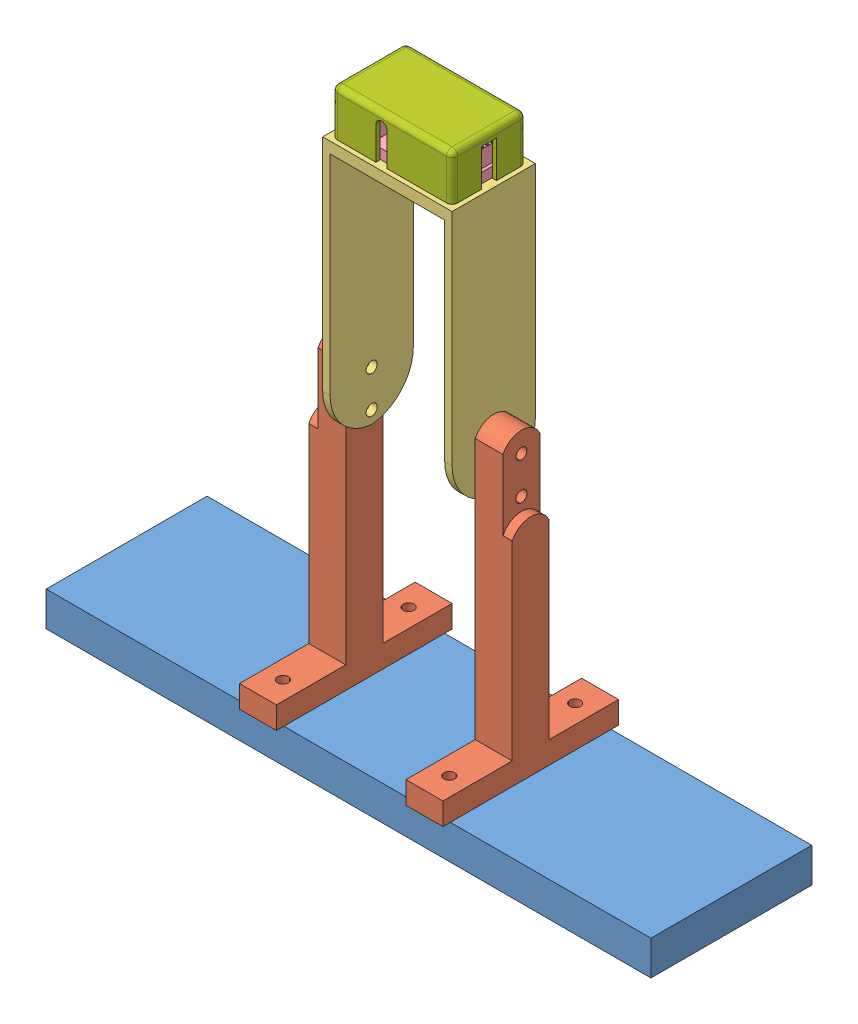
SolidWorks assembly MeasuringAssy-V3, configuration Default. Lengths in mm.
Overall size (327 309.02 95).
11 component instances, 8 part files, 16 mates.
Components (placement in the parent):
- WoodenBase-MeasureAssy-1: WoodenBase-MeasureAssy [Default] at (-5192.5283 0 1838.2238) x (1 0 0) z (0 1 0) size (327 87 18.64)
- Y-Bracket_Frame-1: Y-Bracket_Frame [Default] at (-35 299.8874 0) x (0 0 1) z (-1 0 0) size (95 159.42 20)
- MeasurerAssyStand+Bracket-1: MeasurerAssyStand+Bracket [Default] at (-161.8732 284.1674 335.0527) x (1 0 0) z (0 0 -1) size (70 143.98 45)
- Y-Bracket_Frame-2: Y-Bracket_Frame [Default] at (35 299.8874 0) x (0 0 -1) z (1 0 0) size (95 159.42 20)
- MeasuringModule-V3-1: MeasuringModule-V3 [Default] at (0 284.1674 0) x (0 0 -1) z (1 0 0) size (35 21.85 67.06)
  - MeasuringRigBody-V3-1: MeasuringRigBody-V3 [Default] at origin size (35 21.85 60)
  - Laser-1: Laser [Default] at (0 14.65 17.075) size (15.2 9.36 26.73)
  - Laser-Sensor-V2-1: Laser-Sensor-V2 [Default] at (2.36 12.57 -26.6736) x (0 1 0) z (1 0 0) size (14.36 10.9 18.55)
  - MeasuringRigCover-V3-1: MeasuringRigCover-V3 [Default] at origin size (40 24.85 65)
- SiliconInsert-1: SiliconInsert [Default] at (-5.6236 302.0174 -10.12) x (0.986878 0.16147 0) z (0 0 1) size (4 4 4.12)
- SiliconInsert-2: SiliconInsert [Default] at (-5.6236 302.0174 1.38) x (0.211865 0.977299 0) z (0 0 1) size (4 4 4.12)
Mates (geometry in assembly coordinates):
- Coincident1: coincident anti-aligned: plane of WoodenBase-MeasureAssy-1 through (-5192.5283 0 1838.2238) normal (0 -1 0)
- Coincident2: coincident: line of WoodenBase-MeasureAssy-1 through (0 18.64 -43.5) axis (0 0 1)
- Coincident3: coincident: line of WoodenBase-MeasureAssy-1 through (-163.5 18.64 0) axis (1 0 0)
- Coincident4: coincident anti-aligned: plane of WoodenBase-MeasureAssy-1 through (-5192.5283 18.64 1838.2238) normal (0 1 0); plane of Y-Bracket_Frame-1 through (-55 18.64 -47.5) normal (0 -1 0)
- Concentric1: concentric aligned: circle of WoodenBase-MeasureAssy-1; circle of Y-Bracket_Frame-1
- Concentric2: concentric aligned: circle of WoodenBase-MeasureAssy-1; circle of Y-Bracket_Frame-1
- Coincident17: coincident anti-aligned: line of Y-Bracket_Frame-1 through (-35 18.64 0) axis (0 1 0); line of MeasurerAssyStand+Bracket-1 through (-35 284.1674 0) axis (0 -1 0)
- Coincident18: coincident anti-aligned: plane of Y-Bracket_Frame-1 through (-35 167.0574 0) normal (1 0 0); plane of MeasurerAssyStand+Bracket-1 through (-35 278.1674 -22.5) normal (-1 0 0)
- Concentric3: concentric anti-aligned: cylinder of Y-Bracket_Frame-1 through (-55 167.0574 0) axis (1 0 0) radius 2.925; cylinder of MeasurerAssyStand+Bracket-1 through (35.001 167.0574 0) axis (-1 0 0) radius 3
- Coincident19: coincident anti-aligned: plane of MeasurerAssyStand+Bracket-1 through (-161.8732 284.1674 335.0527) normal (0 1 0); plane of MeasuringModule-V3-1/MeasuringRigBody-V2-1 through (0 284.1674 0) normal (0 -1 0)
- Concentric4: concentric anti-aligned: cylinder of MeasurerAssyStand+Bracket-1 through (27 284.1684 -14.5) axis (0 -1 0) radius 1.5; circle of MeasuringModule-V2-1/MeasuringRigBody-V2-1
- Coincident22: coincident anti-aligned: circle of MeasurerAssyStand+Bracket-1; cylinder of MeasuringModule-V3-1/MeasuringRigBody-V2-1 through (27 284.1674 14.5) axis (0 1 0) radius 1.5
- Concentric5: concentric aligned: cylinder of MeasuringModule-V3-1/MeasuringRigBody-V3-1 through (-5.6236 302.0174 -6) axis (0 0 -1) radius 2; cylinder of SiliconInsert-1 through (-5.6236 302.0174 -6) axis (0 0 -1) radius 2
- Coincident23: coincident anti-aligned: plane of MeasuringModule-V3-1/MeasuringRigBody-V3-1 through (-5.6236 302.0174 -6) normal (0 0 -1); plane of SiliconInsert-1 through (-5.6236 302.0174 -6) normal (0 0 1)
- Concentric6: concentric: cylinder of MeasuringModule-V3-1/MeasuringRigBody-V3-1 through (-5.6236 302.0174 5.5) axis (0 0 -1) radius 2; cylinder of SiliconInsert-2 through (-5.6236 302.0174 5.5) axis (0 0 -1) radius 2
- Coincident24: coincident anti-aligned: plane of MeasuringModule-V3-1/MeasuringRigBody-V3-1 through (-5.6236 302.0174 5.5) normal (0 0 -1); plane of SiliconInsert-2 through (-5.6236 302.0174 5.5) normal (0 0 1)
